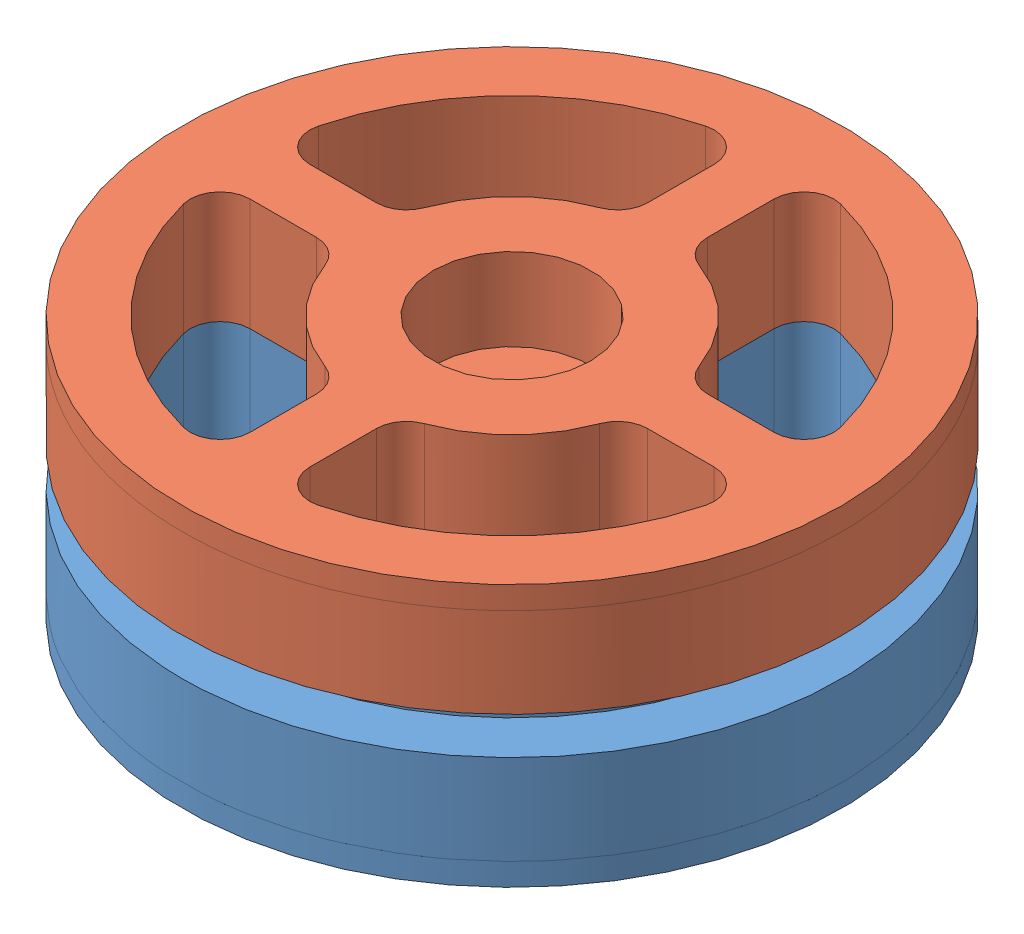
SolidWorks assembly tread-wheel, configuration Free. Lengths in mm.
Overall size (44 17.5 44).
2 component instances, 2 part files, 7 mates.
Components (placement in the parent):
- tread-wheel-rear-1: tread-wheel-rear [Free] at origin size (44 10 44)
- tread-wheel-front-1: tread-wheel-front [Free] at (0 10 0) x (1 0 0) z (0 1 0) size (44 44 10)
Mates (geometry in assembly coordinates):
- Coincident1: coincident anti-aligned: plane of tread-wheel-rear-1 through (0 0 0) normal (0 -1 0); plane of assembly through (0 0 0) normal (0 1 0)
- Coincident2: coincident aligned: plane of tread-wheel-rear-1 through (0 0 0) normal (0 0 1); plane of assembly through (0 0 0) normal (0 0 1)
- Coincident3: coincident aligned: plane of tread-wheel-rear-1 through (0 0 0) normal (1 0 0); plane of assembly through (0 0 0) normal (1 0 0)
- InPlace1: in place: plane of tread-wheel-rear-1 through (0 10 0) normal (0 1 0); plane of tread-wheel-front-1 through (0 10 0) normal (0 1 0); moOrthogonalPlaneRef_w of tread-wheel-rear-1 through (0 10 0) normal (0 1 0); plane of tread-wheel-front-1 through (0 10 0) normal (0 0 -1); plane of tread-wheel-rear-1 through (0 10 0) normal (0 1 0); line of tread-wheel-front-1 through (-55 0 10) axis (0 1 0); plane of tread-wheel-rear-1 through (0 10 0) normal (0 1 0); unknown of tread-wheel-front-1
- Coincident4: coincident aligned: plane of tread-wheel-rear-1; plane of tread-wheel-front-1
- Coincident5: coincident aligned: moOrthogonalPlaneRef_w of tread-wheel-rear-1 through (0 10 0) normal (0 0 -1); plane of tread-wheel-front-1 through (0 10 0) normal (0 0 -1)
- Coincident6: coincident anti-aligned: moOrthogonalPlaneRef_w of tread-wheel-rear-1 through (0 10 0) normal (-1 0 0); plane of tread-wheel-front-1
